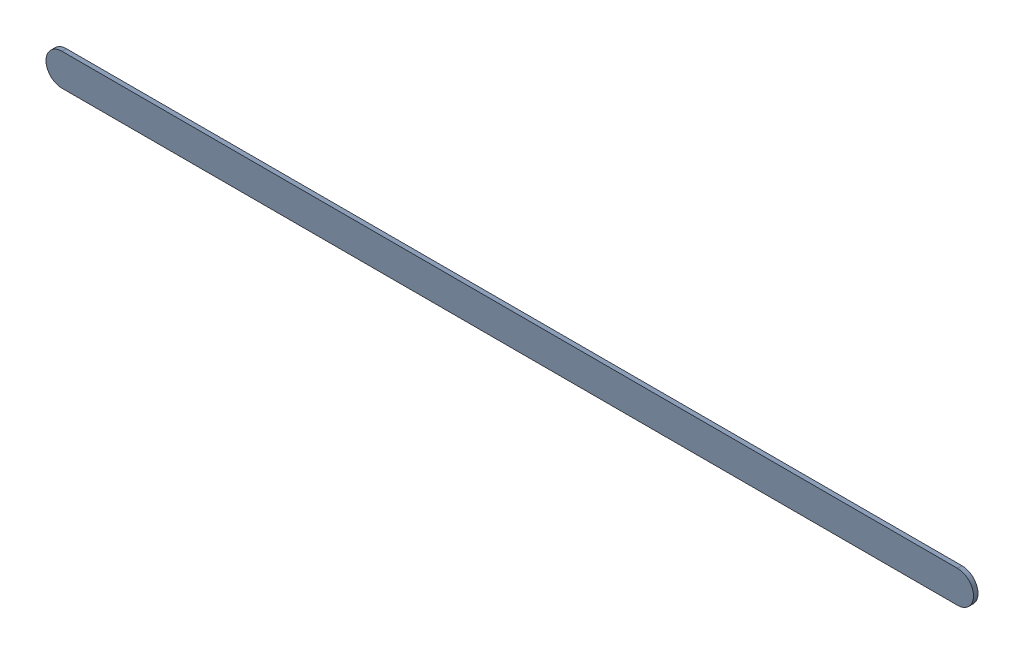
SolidWorks assembly Track (22.8mm,52.7mm)(29.9mm,52.7mm) on Top Layer, configuration Predeterminado. Lengths in mm.
Overall size (7.35 0.25 0.04).
2 component instances, 1 part files, 0 mates.
Components (placement in the parent):
- Track (22.8mm,52.7mm)(29.9mm,52.7mm) on Top Layer-1-1: Track (22.8mm,52.7mm)(29.9mm,52.7mm) on Top Layer-1 [Predeterminado] at (-68.317 -44.187 -0.0457) size (7.35 0.25 0.04)
  - Track (22.8mm,52.7mm)(29.9mm,52.7mm) on Top Layer-Part-1-1: Track (22.8mm,52.7mm)(29.9mm,52.7mm) on Top Layer-Part-1 [Predeterminado] at origin size (7.35 0.25 0.04)
